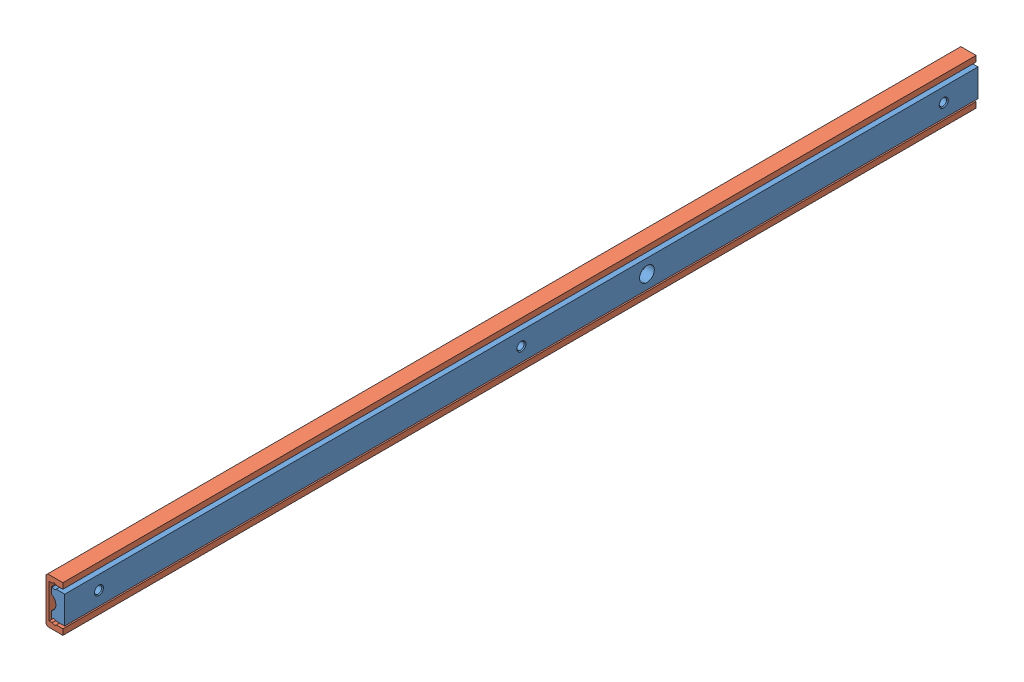
SolidWorks assembly SAR240, configuration Default. Lengths in mm.
Overall size (9.5 22.1 600).
2 component instances, 2 part files, 0 mates.
Components (placement in the parent):
- SAR2-40_r-1: SAR2-40_r [Default] at origin size (6 12.1 400)
- SAR2-40_b-1: SAR2-40_b [Default] at (5 -3.95 0) size (7.4 20 400)
